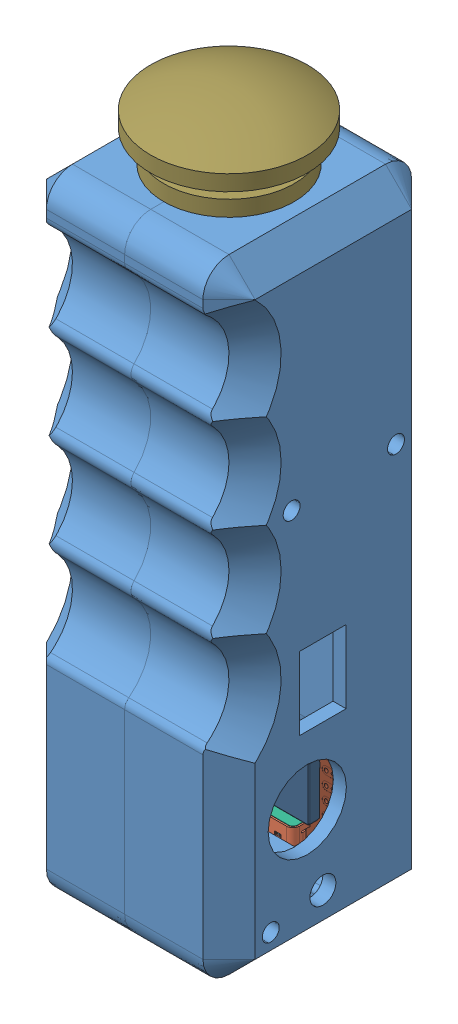
SolidWorks assembly ButtonCase, configuration Default. Lengths in mm.
Overall size (40.01 132.5 40).
34 component instances, 30 part files, 8 mates.
Components (placement in the parent):
- ButtonCase-1: ButtonCase [Default] at (-20 0 0) size (40.01 119.5 40)
- Seeed Studio XIAO-ESP32-C3.step-1: Seeed Studio XIAO-ESP32-C3.step [Default] at (-6.1114 -105.6733 -12) x (0 -1 0) z (-1 0 0) size (22.46 4.21 17.78)
  - USB TYPE C PORT.step-1: USB TYPE C PORT.step [Default] at (6.4897 2.605 -6.1114) x (0 0 -1) z (0 -1 0) size (8.94 7.9 4.2)
    - USB TYPE C PORT (1).step-1: USB TYPE C PORT (1).step [Default] at origin size (8.94 7.9 4.2)
      - BOSS-EXTRUDE14_8_.step-1: BOSS-EXTRUDE14_8_.step [Default] at origin size (0.6 1 0.3)
      - BOSS-EXTRUDE7_4_.step-1: BOSS-EXTRUDE7_4_.step [Default] at origin size (0.3 3.78 0.75)
      - BOSS-EXTRUDE7_3_.step-1: BOSS-EXTRUDE7_3_.step [Default] at origin size (0.3 3.78 0.75)
      - BOSS-EXTRUDE14_4_.step-1: BOSS-EXTRUDE14_4_.step [Default] at origin size (0.3 1 0.3)
      - BOSS-EXTRUDE14_2_.step-1: BOSS-EXTRUDE14_2_.step [Default] at origin size (0.6 1 0.3)
      - BOSS-EXTRUDE14_11_.step-1: BOSS-EXTRUDE14_11_.step [Default] at origin size (0.3 1 0.3)
      - BOSS-EXTRUDE7_7_.step-1: BOSS-EXTRUDE7_7_.step [Default] at origin size (0.3 3.78 0.75)
      - BOSS-EXTRUDE14_9_.step-1: BOSS-EXTRUDE14_9_.step [Default] at origin size (0.3 1 0.3)
      - BOSS-EXTRUDE14_3_.step-1: BOSS-EXTRUDE14_3_.step [Default] at origin size (0.3 1 0.3)
      - BOSS-EXTRUDE14_7_.step-1: BOSS-EXTRUDE14_7_.step [Default] at origin size (0.6 1 0.3)
      - MIRROR2.step-1: MIRROR2.step [Default] at origin size (6.7 4.6 0.7)
      - BOSS-EXTRUDE14_5_.step-1: BOSS-EXTRUDE14_5_.step [Default] at origin size (0.3 1 0.3)
      - BOSS-EXTRUDE14_12_.step-1: BOSS-EXTRUDE14_12_.step [Default] at origin size (0.3 1 0.3)
      - BOSS-EXTRUDE7_8_.step-1: BOSS-EXTRUDE7_8_.step [Default] at origin size (0.3 3.78 0.75)
      - BOSS-EXTRUDE7_1_.step-1: BOSS-EXTRUDE7_1_.step [Default] at origin size (0.3 3.78 0.75)
      - BOSS-EXTRUDE14_10_.step-1: BOSS-EXTRUDE14_10_.step [Default] at origin size (0.3 1 0.3)
      - BOSS-EXTRUDE7_9_.step-1: BOSS-EXTRUDE7_9_.step [Default] at origin size (0.3 3.78 0.75)
      - BOSS-EXTRUDE14_6_.step-1: BOSS-EXTRUDE14_6_.step [Default] at origin size (0.6 1 0.3)
      - CHAMFER9.step-1: CHAMFER9.step [Default] at origin size (8.94 7.3 4.2)
      - BOSS-EXTRUDE14_1_.step-1: BOSS-EXTRUDE14_1_.step [Default] at origin size (0.3 1 0.3)
      - BOSS-EXTRUDE7_6_.step-1: BOSS-EXTRUDE7_6_.step [Default] at origin size (0.3 3.78 0.75)
      - BOSS-EXTRUDE7_2_.step-1: BOSS-EXTRUDE7_2_.step [Default] at origin size (0.3 3.78 0.75)
      - CUT-EXTRUDE5.step-1: CUT-EXTRUDE5.step [Default] at origin size (8.54 2 3.59)
      - BOSS-EXTRUDE7_5_.step-1: BOSS-EXTRUDE7_5_.step [Default] at origin size (0.3 3.78 0.75)
  - U.FL Connector v1.step-1: U.FL Connector v1.step [Default] at (-7.041 1 -6.1015) x (0 0 1) z (-1 0 0) size (3 1.3 2.6)
  - Button (1).step-1: Button (1).step [Default] at origin size (2.5 1.7 4.3)
  - Shield.step-1: Shield.step [Default] at origin size (10.6 2.7 12.6)
  - Button (1).step-2: Button (1).step [Default] at (0 0 8.89) size (2.5 1.7 4.3)
  - Seeed Studio XIAO-ESP32-C3.step-1: Seeed Studio XIAO-ESP32-C3.step [Default] at origin size (20.96 1 17.78)
- TopButton-1: TopButton [Default] at origin size (30 35 30)
Mates (geometry in assembly coordinates):
- Coincident2: coincident aligned: plane of ButtonCase-1 through (0 -70.5 25.6) normal (1 0 0)
- Coincident3: coincident aligned: plane of ButtonCase-1 through (0 0 20) normal (0 1 0)
- Coincident4: coincident aligned: plane of ButtonCase-1 through (-20 0 0) normal (0 0 1)
- Symmetric2: symmetric aligned: plane of Seeed Studio XIAO-ESP32-C3.step-1/Seeed Studio XIAO-ESP32-C3.step-1 through (8.89 -116.05 -12) normal (1 0 0); plane of Seeed Studio XIAO-ESP32-C3.step-1/Seeed Studio XIAO-ESP32-C3.step-1 through (-8.89 -115.3515 -12) normal (-1 0 0)
- Coincident7: coincident anti-aligned: plane of ButtonCase-1 through (-20.002 -97 -9.5) normal (0 -1 0); plane of Seeed Studio XIAO-ESP32-C3.step-1/Seeed Studio XIAO-ESP32-C3.step-1 through (6.985 -97 -12) normal (0 1 0)
- Coincident8: coincident anti-aligned: plane of ButtonCase-1 through (-5 -112.5 -11) normal (0 0 1); plane of Seeed Studio XIAO-ESP32-C3.step-1/USB TYPE C PORT.step-1/USB TYPE C PORT (1).step-1/CHAMFER9.step-1 through (-4.47 -119.463 -11) normal (0 0 -1)
- Coincident9: coincident anti-aligned: plane of ButtonCase-1 through (0 0 20) normal (0 1 0); plane of TopButton-1 through (0 0 -11) normal (0 -1 0)
- Concentric1: concentric anti-aligned: cylinder of ButtonCase-1 through (0 -119.501 0) axis (0 1 0) radius 11.25; cylinder of TopButton-1 through (0 0 0) axis (0 -1 0) radius 11
